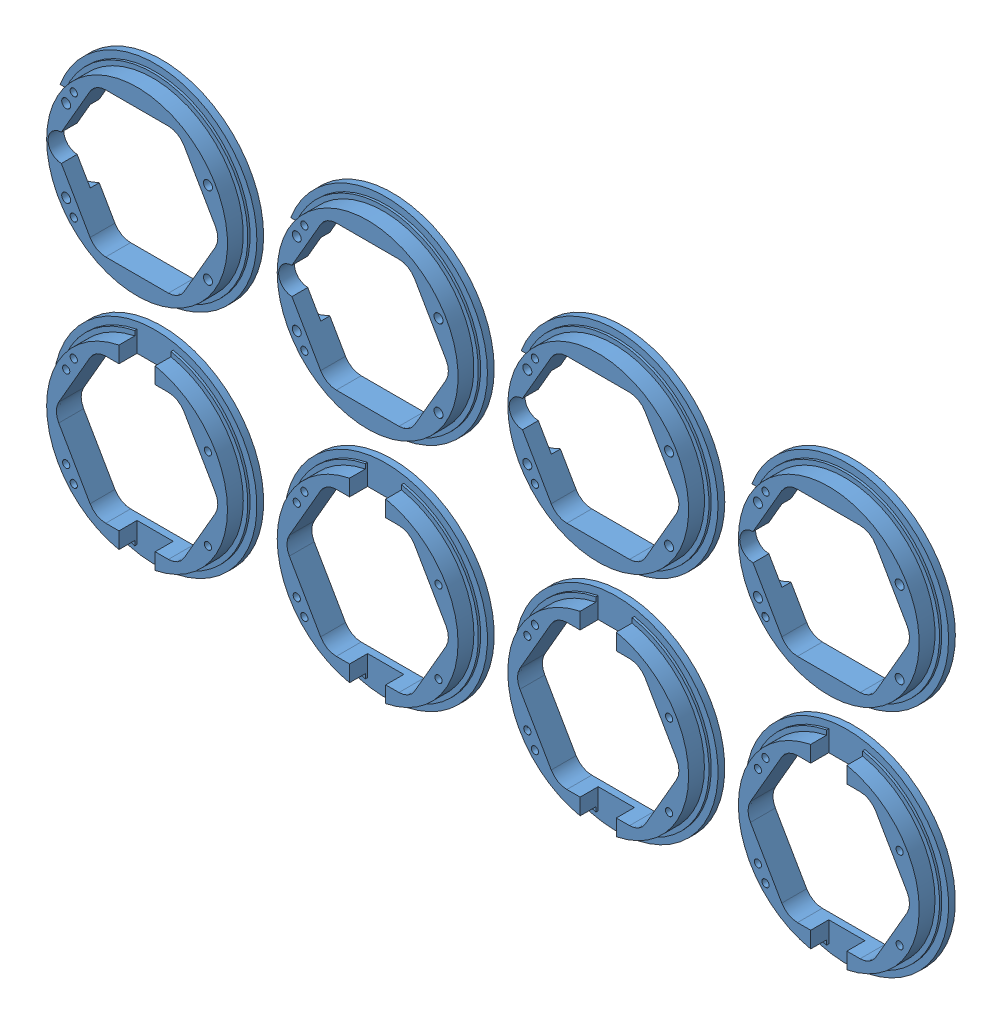
SolidWorks assembly Fraesen1, configuration Standard. Lengths in mm.
Overall size (198 96 5.68).
8 component instances, 1 part files, 3 mates.
Components (placement in the parent):
- Rad-Nabe-1: Rad-Nabe [Außen-Lenkbar] at origin size (45 45 5.5)
- Rad-Nabe-2: Rad-Nabe [Innen-Angetrieben] at (0 51 0) size (43.53 45 5.68)
- Rad-Nabe-3: Rad-Nabe [Außen-Lenkbar] at (51 0 0) size (45 45 5.5)
- Rad-Nabe-4: Rad-Nabe [Außen-Lenkbar] at (102 0 0) size (45 45 5.5)
- Rad-Nabe-5: Rad-Nabe [Außen-Lenkbar] at (153 0 0) size (45 45 5.5)
- Rad-Nabe-6: Rad-Nabe [Innen-Angetrieben] at (51 51 0) size (43.53 45 5.68)
- Rad-Nabe-7: Rad-Nabe [Innen-Angetrieben] at (102 51 0) size (43.53 45 5.68)
- Rad-Nabe-8: Rad-Nabe [Innen-Angetrieben] at (153 51 0) size (43.53 45 5.68)
Mates (geometry in assembly coordinates):
- Deckungsgleich1: coincident aligned: plane of Rad-Nabe-1 through (0 22.5 -5.5) normal (0 0 -1); plane of Rad-Nabe-2 through (0 73.5 -5.5) normal (0 0 -1)
- Deckungsgleich2: coincident aligned: plane of Rad-Nabe-1 through (0 0 0) normal (1 0 0); plane of Rad-Nabe-2 through (0 51 0) normal (1 0 0)
- Abstand1: distance = 51 mm aligned: plane of Rad-Nabe-1 through (0 0 0) normal (0 1 0); plane of Rad-Nabe-2 through (0 51 0) normal (0 1 0)
